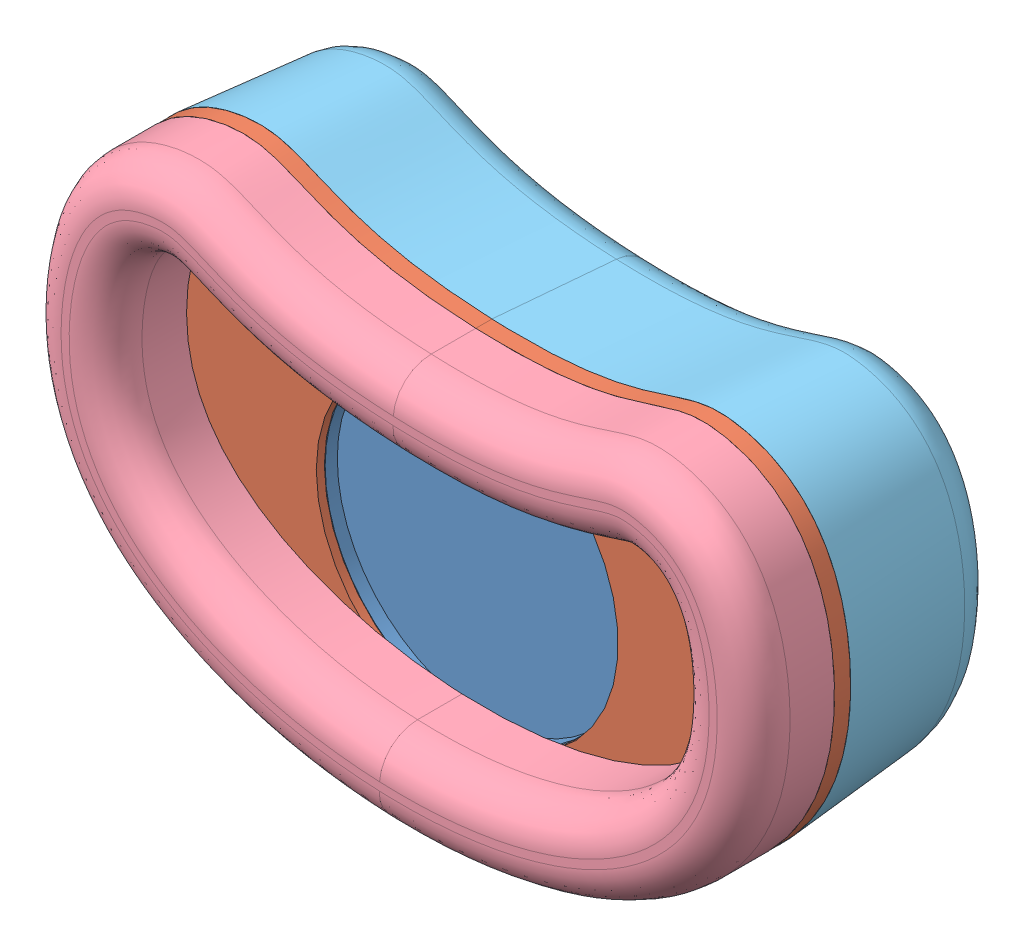
SolidWorks assembly assambly speaker, configuration Default. Lengths in mm.
Overall size (101.14 69.03 42.89).
7 component instances, 7 part files, 16 mates.
Components (placement in the parent):
- speakertje-1: speakertje [Default] at (38.7 -2.6228 10.2754) x (0 1 0) z (-1 0 0) size (38.7 4.9 38.7)
- speaker houder-1: speaker houder [Default] at (37.6436 -27.6005 9.2754) x (0.042255 0.999107 0) z (0 0 1) size (56.7 91.78 17)
- speaker houder binnenkant-1: speaker houder binnenkant [Default] at (38.8382 0.6437 22.4754) x (0.042255 0.999107 0) z (0 0 -1) size (42.77 77.51 6.81)
- mooi kussentje-3: mooi kussentje [Default] at (38.6015 -3.0858 11.2754) x (0.042255 0.999107 0) z (0 0 1) size (64.93 98.49 10.39)
- speaker houder kap-3: speaker houder kap [Default] at (38.8382 0.6437 9.2754) x (0.042255 0.999107 0) z (0 0 -1) size (63.1 97.32 20.59)
- draaischijfhouder-1: draaischijfhouder [Default] at (38.7 -2.6228 -10.7246) x (-1 0 0) z (0 -1 0) size (30 5 30)
- draaischijf-2: draaischijf [Default] at (38.7 -2.6228 -11.2246) x (0.033941 -0.999424 0) z (0.999424 0.033941 0) size (16 10 16)
Mates (geometry in assembly coordinates):
- Coincident1: coincident anti-aligned: plane of speakertje-1 through (38.7 -2.6228 10.2754) normal (0 0 1); plane of speaker houder-1 through (38.7 -2.6228 10.2754) normal (0 0 -1)
- Concentric1: concentric anti-aligned: circle of speakertje-1; circle of speaker houder-1
- Coincident5: coincident anti-aligned: plane of speaker houder-1 through (-4.5182 -3.2347 11.2754) normal (0 0 1); plane of mooi kussentje-3 through (-4.5182 -3.2347 11.2754) normal (0 0 -1)
- Tangent9: tangent: curve of speaker houder-1; curve of mooi kussentje-3
- Tangent10: tangent: curve of speaker houder-1; curve of mooi kussentje-3
- Concentric2: concentric anti-aligned: cylinder of speaker houder-1 through (13.5111 -6.562 4.2754) axis (0 0 1) radius 2; cylinder of speaker houder binnenkant-1 through (13.5111 -6.562 9.2754) axis (0 0 -1) radius 2
- Concentric3: concentric anti-aligned: cylinder of speaker houder-1 through (66.3097 11.2229 4.2754) axis (0 0 1) radius 2; cylinder of speaker houder binnenkant-1 through (66.3097 11.2229 9.2754) axis (0 0 -1) radius 2
- Coincident6: coincident anti-aligned: plane of speaker houder-1 through (66.3097 11.2229 4.2754) normal (0 0 -1); plane of speaker houder binnenkant-1 through (81.7122 -6.8817 4.2754) normal (0 0 1)
- Coincident8: coincident anti-aligned: plane of speaker houder-1 through (-4.5182 -3.2347 9.2754) normal (0 0 -1); plane of speaker houder kap-2 through (81.7122 -6.8817 9.2754) normal (0 0 1)
- Tangent11: tangent: curve of speaker houder-1; curve of speaker houder kap-2
- Tangent12: tangent: curve of speaker houder-1; curve of speaker houder kap-2
- Coincident9: coincident anti-aligned: plane of speaker houder kap-2 through (81.7122 -6.8817 -10.7246) normal (0 0 -1); plane of draaischijfhouder-1 through (38.7 -12.6228 -10.7246) normal (0 0 1)
- Concentric4: concentric aligned: cylinder of speaker houder kap-2 through (38.7 -2.6228 -11.2246) axis (0 0 1) radius 10; cylinder of draaischijfhouder-1 through (38.7 -2.6228 -10.7246) axis (0 0 1) radius 10
- Concentric5: concentric anti-aligned: cylinder of draaischijfhouder-1 through (38.7 -2.6228 -10.7246) axis (0 0 1) radius 2; cylinder of draaischijf-2 through (38.7 -2.6228 -21.2246) axis (0 0 -1) radius 2
- Concentric6: concentric anti-aligned: cylinder of draaischijfhouder-1 through (38.7 -2.6228 -10.7246) axis (0 0 1) radius 10; cylinder of draaischijf-2 through (38.7 -2.6228 -21.2246) axis (0 0 -1) radius 8
- Coincident10: coincident anti-aligned: plane of speaker houder kap-2 through (38.7 -2.6228 -11.2246) normal (0 0 -1); plane of draaischijf-2 through (38.7 -2.6228 -11.2246) normal (0 0 1)
